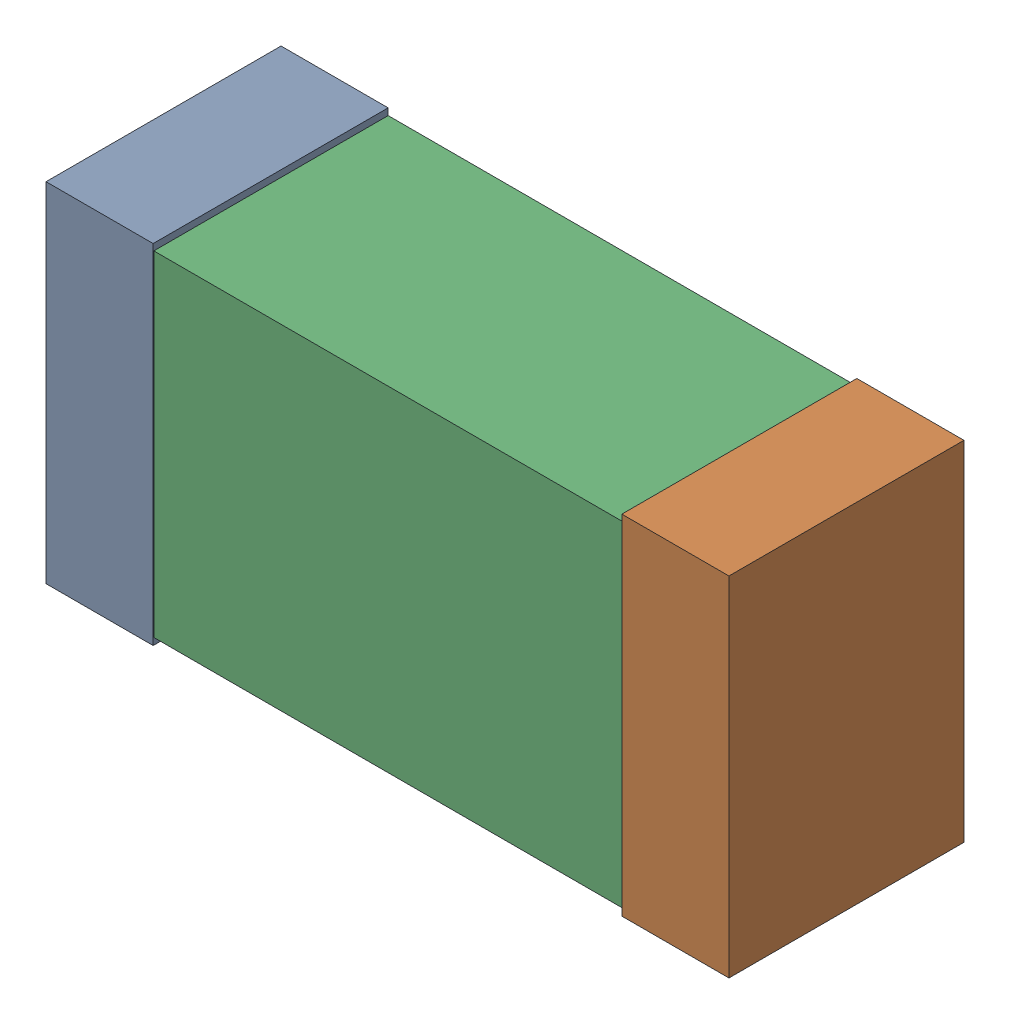
SolidWorks assembly C38, configuration Default. Lengths in mm.
Overall size (1.02 0.52 0.35).
6 component instances, 2 part files, 0 mates.
Components (placement in the parent):
- 870940480-1: 870940480 [Default] at (49.023 38.174 0) size (0.16 0.52 0.35)
  - Extruded-1: Extruded [Default] at origin size (0.16 0.52 0.35)
- 870940480-2: 870940480 [Default] at (49.883 38.174 0) size (0.16 0.52 0.35)
  - Extruded-1: Extruded [Default] at origin size (0.16 0.52 0.35)
- 870940640-1: 870940640 [Default] at (49.453 38.174 0) size (1 0.5 0.35)
  - Extruded_2-1: Extruded_2 [Default] at origin size (1 0.5 0.35)
